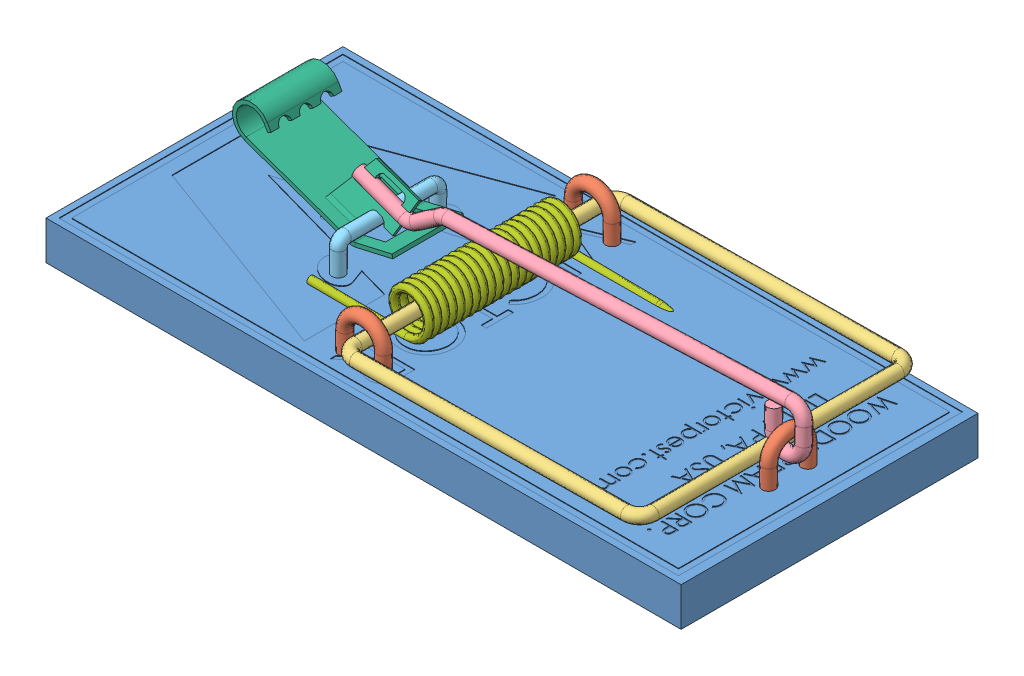
SolidWorks assembly mousetrap, configuration Défaut. Lengths in mm.
Overall size (98.4 21.67 46).
9 component instances, 7 part files, 19 mates.
Components (placement in the parent):
- base-1: base [Défaut] at origin size (98.4 6 46)
- pin-1: pin [Défaut] at (44 6 -5.3) x (-1 0 0) z (0 0 -1) size (8 7 2)
- pin-2: pin [Défaut] at (44 6 -40.7) x (-1 0 0) z (0 0 -1) size (8 7 2)
- pin-3: pin [Défaut] at (92 6 -23) x (-0.013039 0 0.999915) z (-0.999915 0 -0.013039) size (8 7 2)
- trap-1: trap [Défaut] at (66.9989 9.2282 -23) x (0 0 1) z (-0.009923 0.999951 0) size (44 48 2)
- arm-1: arm [Défaut] at (89.5696 14.2374 -23.2051) x (0.999591 0.024114 -0.015382) z (0.014267 0.045739 0.998852) size (69.37 8.9 2)
- large_pin-1: large_pin [Défaut] at (30 6 -30.7) x (0 0 1) z (-1 0 0) size (17.4 5.5 2)
- release-1: release [Défaut] at (14.2602 17.032 -28.5) x (0.942578 -0.333987 0) z (0 0 1) size (26 6.8 11)
- spring-1: spring [Défaut] at (44 9 -36.0414) x (0 0 1) z (0.011661 0.999932 0) size (25.2 40.12 9.19)
Mates (geometry in assembly coordinates):
- Coïncidente1: coincident anti-aligned: plane of base-1 through (0 6 0) normal (0 1 0); plane of pin-1 through (41 6 -5.3) normal (0 -1 0)
- Distance1: distance = 44 mm: point of pin-1; plane of base-1 through (0 6 0) normal (-1 0 0)
- Distance2: distance = 5.3 mm: point of pin-1; plane of base-1 through (0 6 0) normal (0 0 1)
- Coïncidente5: coincident anti-aligned: plane of base-1 through (0 6 0) normal (0 1 0); plane of pin-2 through (41 6 -40.7) normal (0 -1 0)
- Distance3: distance = 5.3 mm: point of pin-2; plane of base-1 through (0 6 -46) normal (0 0 -1)
- Distance4: distance = 44 mm: point of pin-2; plane of base-1 through (0 6 0) normal (-1 0 0)
- Coïncidente10: coincident anti-aligned: plane of base-1 through (0 6 0) normal (0 1 0); plane of pin-3 through (92.0391 6 -25.9997) normal (0 -1 0)
- Distance5: distance = 6.4 mm: point of pin-3; plane of base-1 through (98.4 6 0) normal (1 0 0)
- Distance6: distance = 23 mm: plane of base-1 through (0 6 0) normal (0 0 1); point of pin-3
- Coaxiale2: concentric aligned: circle of pin-1; cylinder of trap-1 through (44 9 -4) axis (0 0 -1) radius 1
- Coaxiale3: concentric aligned: circle of pin-2; cylinder of trap-1 through (44 9 -4) axis (0 0 -1) radius 1
- Coïncidente12: coincident: point of pin-3; point of arm-1
- Coïncidente13: coincident anti-aligned: plane of base-1 through (0 6 0) normal (0 1 0); plane of large_pin-1 through (30 6 -30.7) normal (0 -1 0)
- Coaxiale5: concentric anti-aligned: cylinder of large_pin-1 through (30 10.5 -29.7) axis (0 0 1) radius 1; cylinder of release-1 through (30 10.5 -17.5) axis (0 0 -1) radius 1.4
- Distance12: distance = 30 mm: point of large_pin-1; line of base-1 through (0 6 0) axis (0 0 -1)
- Distance14: distance = 15.3 mm: line of base-1 through (98.4 0 6) axis (0 1 0); point of large_pin-1
- Distance15: distance = 17.5 mm aligned: plane of release-1 through (30.314 9.1357 -17.5) normal (0 0 1); plane of base-1 through (0 6 0) normal (0 0 1)
- Coaxiale7: concentric anti-aligned: axis of trap-1 through (44 9 -4) axis (0 0 -1); circle of spring-1
- LimitAngle1: limit planar angle = 0.34053 rad anti-aligned: plane of release-1 through (13.2916 14.2985 -17.5) normal (-0.333987 -0.942578 0); plane of base-1 through (29.7079 5.9 -13.2879) normal (0 1 0)
